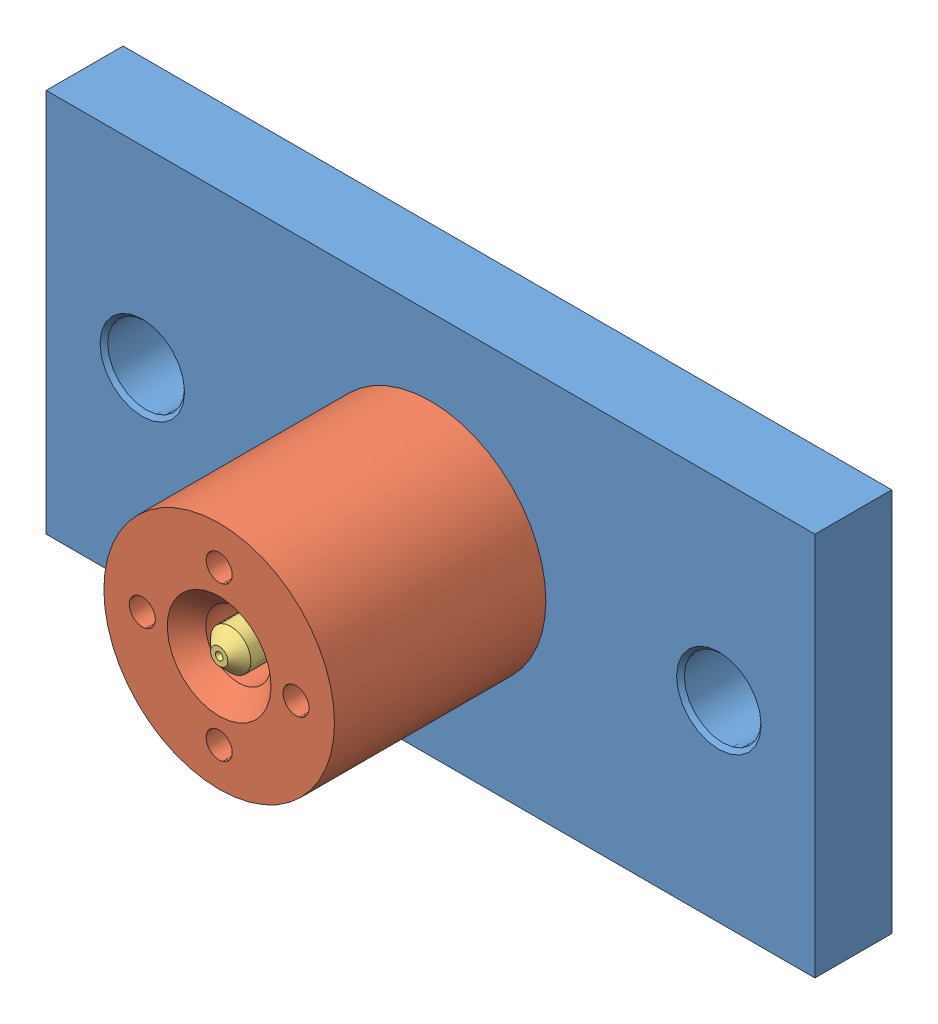
SolidWorks assembly carbon assembly, configuration Default. Lengths in mm.
Overall size (200 100 75).
3 component instances, 3 part files, 5 mates.
Components (placement in the parent):
- seating plate-1: seating plate [Default] at (70.2506 96.7648 134.6267) size (200 100 20)
- carbon bush die-1: carbon bush die [Default] at (70.2506 96.7648 189.6267) x (1 0 0) z (0 1 0) size (60 60 60)
- die inner pin-1: die inner pin [Default] at (70.2506 96.7648 155.6267) x (0 0 -1) z (1 0 0) size (75 25 25)
Mates (geometry in assembly coordinates):
- Coincident1: coincident anti-aligned: plane of seating plate-1 through (70.2506 96.7648 129.6267) normal (0 0 1); plane of carbon bush die-1 through (70.2506 96.7648 129.6267) normal (0 0 -1)
- Concentric1: concentric anti-aligned: cylinder of seating plate-1 through (70.2506 96.7648 129.6267) axis (0 0 1) radius 27.5; cylinder of carbon bush die-1 through (70.2506 96.7648 134.6267) axis (0 0 -1) radius 27.5
- Concentric2: concentric aligned: cylinder of seating plate-1 through (70.2506 116.7648 114.6267) axis (0 0 1) radius 4; cylinder of carbon bush die-1 through (70.2506 116.7648 129.6267) axis (0 0 1) radius 3.4
- Concentric4: concentric anti-aligned: cylinder of seating plate-1 through (70.2506 96.7648 124.6267) axis (0 0 -1) radius 11; cylinder of die inner pin-1 through (70.2506 96.7648 187.6267) axis (0 0 1) radius 12.5
- Coincident3: coincident aligned: plane of seating plate-1 through (70.2506 96.7648 114.6267) normal (0 0 -1); plane of die inner pin-1 through (57.7506 96.7648 114.6267) normal (0 0 -1)
